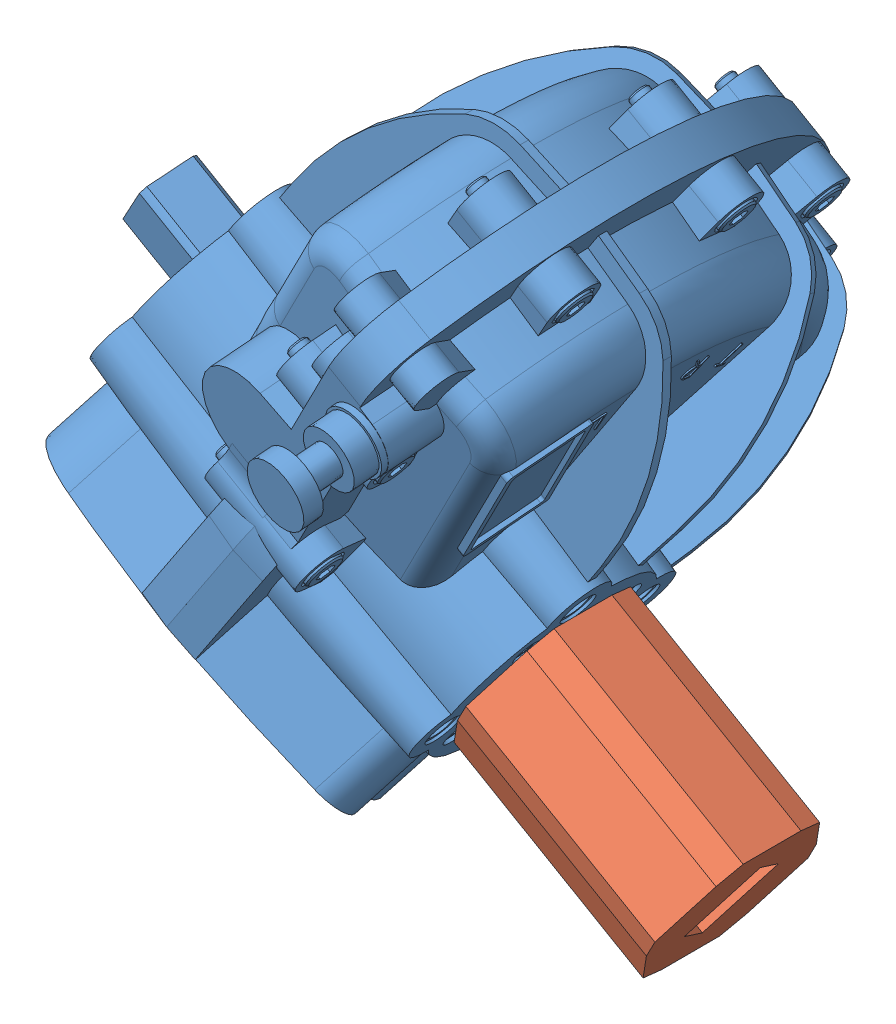
SolidWorks assembly Kinetrol Assembly, configuration Default. Lengths in mm.
Overall size (149.4 168.54 155.11).
2 component instances, 2 part files, 2 mates.
Components (placement in the parent):
- Kinetrol Model 03-1: Kinetrol Model 03 [Default] at (-29.4799 63.262 24.5942) x (0.326888 0.497504 0.803514) z (0.850393 -0.525752 -0.020435) size (123.23 91.4 84)
- Kinetrol Mount-2: Kinetrol Mount [Default] at (-3.9681 47.4895 23.9812) x (0.423009 0.706272 -0.567664) z (-0.312883 -0.474094 -0.823007) size (28.11 35.56 25.4)
Mates (geometry in assembly coordinates):
- Concentric1: concentric aligned: circle of Kinetrol Model 03-1; circle of Kinetrol Mount-2
- Coincident7: coincident anti-aligned: plane of Kinetrol Model 03-1 through (0.0974 54.0206 25.1284) normal (0.850393 -0.525752 -0.020435); plane of Kinetrol Mount-2 through (-3.9681 47.4895 23.9812) normal (-0.850393 0.525752 0.020435)
